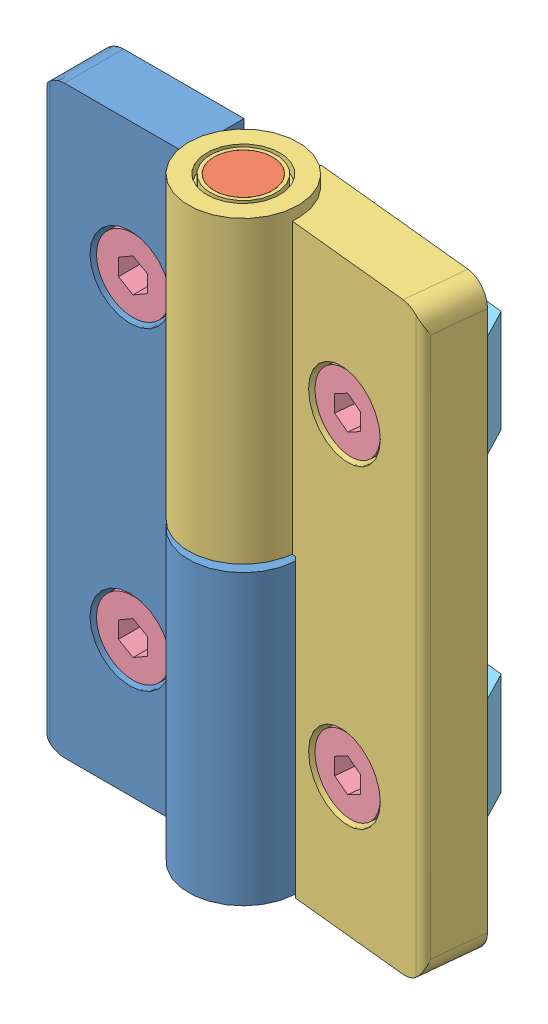
SolidWorks assembly HHPNLK-B6-SET, configuration Default. Lengths in mm.
Overall size (55.68 81.5 26.66).
11 component instances, 5 part files, 24 mates.
Components (placement in the parent):
- hinge_1-1: hinge_1 [Default] at (-5.4713 22.3868 78.8004) size (35 80 15.6)
- perno-1: perno [Default] at (-5.4713 22.3868 78.8004) size (8 81.5 8)
- hinge_2-1: hinge_2 [Default] at (-5.4713 22.3868 78.8004) x (0.994805 0 0.101797) z (-0.101797 0 0.994805) size (35 81.5 15.6)
- screw-1: screw [Default] at (-5.4713 22.3868 78.8004) size (10 10 16)
- nut-1: nut [Default] at (-36.4713 22.3868 78.0004) size (15 14 6.3)
- screw-2: screw [Default] at (25.3677 22.3868 81.9561) x (0.994805 0 0.101797) z (-0.101797 0 0.994805) size (10 10 16)
- screw-3: screw [Default] at (-5.4713 -20.6132 78.8004) size (10 10 16)
- screw-4: screw [Default] at (25.3677 -20.6132 81.9561) x (0.994805 0 0.101797) z (-0.101797 0 0.994805) size (10 10 16)
- nut-2: nut [Default] at (-36.4713 -20.6132 78.0004) size (15 14 6.3)
- nut-3: nut [Default] at (-5.3899 22.3868 78.0045) x (0.994805 0 0.101797) z (-0.101797 0 0.994805) size (15 14 6.3)
- nut-4: nut [Default] at (-5.3899 -20.6132 78.0045) x (0.994805 0 0.101797) z (-0.101797 0 0.994805) size (15 14 6.3)
Mates (geometry in assembly coordinates):
- Concentric1: concentric aligned: cylinder of hinge_1-1 through (-5.4713 -17.6132 78.8004) axis (0 -1 0) radius 4; cylinder of perno-1 through (-5.4713 63.8868 78.8004) axis (0 -1 0) radius 4
- Coincident1: coincident aligned: plane of hinge_1-1 through (-5.4713 -17.6132 78.8004) normal (0 -1 0); plane of perno-1 through (-5.4713 -17.6132 78.8004) normal (0 -1 0)
- Concentric2: concentric anti-aligned: cylinder of perno-1 through (-5.4713 63.8868 78.8004) axis (0 -1 0) radius 4; cylinder of hinge_2-1 through (-5.4713 63.8868 78.8004) axis (0 1 0) radius 4
- Coincident2: coincident aligned: plane of hinge_1-1 through (-5.4713 62.3868 78.8004) normal (0 1 0); plane of hinge_2-1 through (-5.4713 62.3868 78.8004) normal (0 1 0)
- Concentric3: concentric aligned: cylinder of hinge_1-1 through (-20.9713 43.8868 78.8004) axis (0 0 1) radius 3.25; cylinder of screw-1 through (-20.9713 43.8868 62.4004) axis (0 0 1) radius 3
- Concentric4: concentric aligned: circle of hinge_2-1; cylinder of screw-2 through (11.6176 43.8868 64.0634) axis (-0.101797 0 0.994805) radius 3
- Concentric5: concentric aligned: cylinder of hinge_1-1 through (-20.9713 0.8868 78.8004) axis (0 0 1) radius 3.25; cylinder of screw-3 through (-20.9713 0.8868 62.4004) axis (0 0 1) radius 3
- Concentric6: concentric aligned: cylinder of hinge_2-1 through (9.9482 0.8868 80.3782) axis (-0.101797 0 0.994805) radius 3.25; cylinder of screw-4 through (11.6176 0.8868 64.0634) axis (-0.101797 0 0.994805) radius 3
- Coincident3: coincident anti-aligned: plane of hinge_1-1 through (-17.7213 43.8868 74.4004) normal (0 0 1); circle of screw-1
- Coincident4: coincident anti-aligned: plane of hinge_2-1 through (13.6292 43.8868 76.3319) normal (-0.101797 0 0.994805); circle of screw-2
- Coincident5: coincident anti-aligned: plane of hinge_2-1 through (13.6292 0.8868 76.3319) normal (-0.101797 0 0.994805); circle of screw-4
- Coincident6: coincident anti-aligned: plane of hinge_1-1 through (-17.7213 0.8868 74.4004) normal (0 0 1); circle of screw-3
- Coincident7: coincident aligned: plane of screw-1 through (-20.9713 43.8868 62.4004) normal (0 0 -1); plane of nut-1 through (-17.0713 36.8868 62.4004) normal (0 0 -1)
- Concentric7: concentric aligned: cylinder of screw-1 through (-20.9713 43.8868 62.4004) axis (0 0 1) radius 3; cylinder of nut-1 through (-20.9713 43.8868 68.7004) axis (0 0 1) radius 2.4585
- Concentric8: concentric aligned: cylinder of screw-3 through (-20.9713 0.8868 62.4004) axis (0 0 1) radius 3; cylinder of nut-2 through (-20.9713 0.8868 68.7004) axis (0 0 1) radius 2.4585
- Concentric9: concentric aligned: cylinder of screw-2 through (11.6176 43.8868 64.0634) axis (-0.101797 0 0.994805) radius 3; cylinder of nut-3 through (10.9763 43.8868 70.3307) axis (-0.101797 0 0.994805) radius 2.4585
- Concentric10: concentric anti-aligned: cylinder of screw-4 through (11.6176 0.8868 64.0634) axis (-0.101797 0 0.994805) radius 3; circle of nut-4
- Coincident8: coincident aligned: plane of screw-3 through (-20.9713 0.8868 62.4004) normal (0 0 -1); plane of nut-2 through (-17.0713 -6.1132 62.4004) normal (0 0 -1)
- Coincident9: coincident aligned: plane of screw-4 through (11.6176 0.8868 64.0634) normal (0.101797 0 -0.994805); plane of nut-4 through (15.4974 -6.1132 64.4604) normal (0.101797 0 -0.994805)
- Coincident10: coincident aligned: plane of screw-2 through (11.6176 43.8868 64.0634) normal (0.101797 0 -0.994805); plane of nut-3 through (15.4974 36.8868 64.4604) normal (0.101797 0 -0.994805)
- Parallel1: parallel aligned: plane of hinge_2-1 through (-5.4713 62.3868 78.8004) normal (0 1 0); plane of nut-3 through (-5.3899 50.8868 78.0045) normal (0 1 0)
- Parallel2: parallel aligned: plane of nut-1 through (-36.4713 50.8868 78.0004) normal (0 1 0); plane of nut-3 through (-5.3899 50.8868 78.0045) normal (0 1 0)
- Parallel3: parallel aligned: plane of nut-3 through (-5.3899 50.8868 78.0045) normal (0 1 0); plane of nut-4 through (-5.3899 7.8868 78.0045) normal (0 1 0)
- Coincident15: coincident aligned: plane of nut-2 through (-36.4713 7.8868 78.0004) normal (0 1 0); plane of nut-4 through (-5.3899 7.8868 78.0045) normal (0 1 0)
